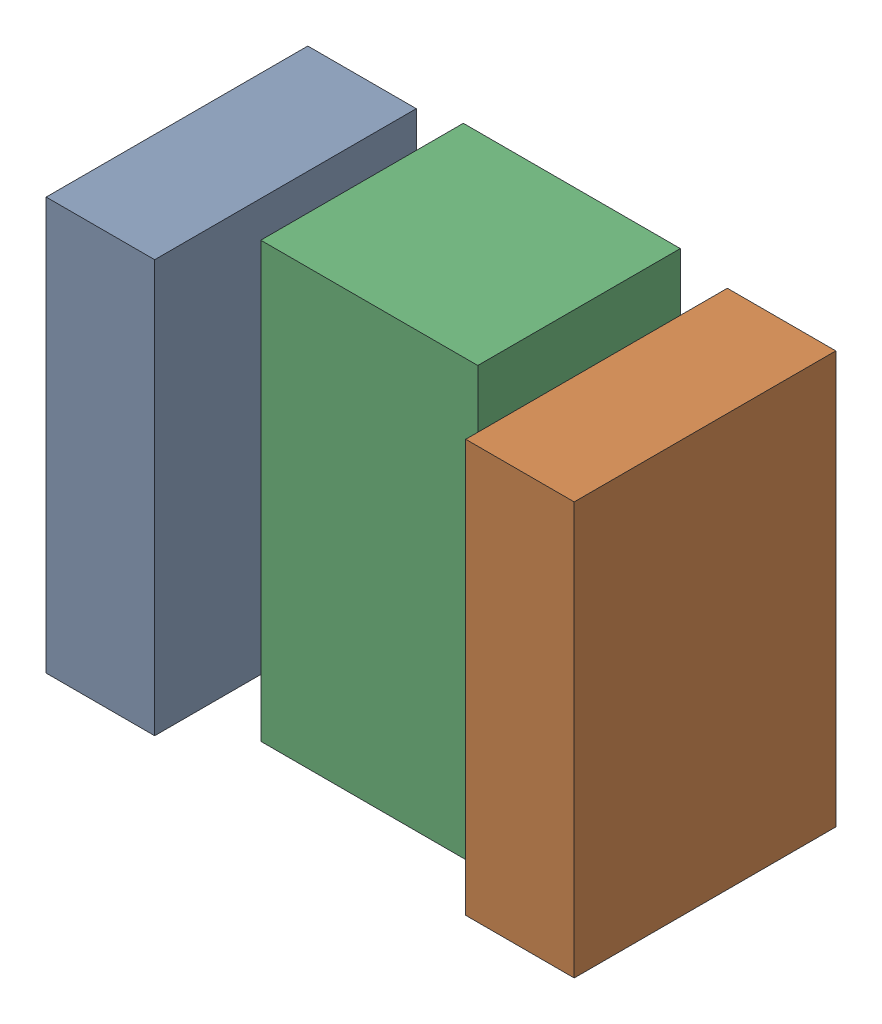
SolidWorks assembly C7_Motor_3Kanaloa_v2.0.0_Motor, configuration Default. Lengths in mm.
Overall size (3.65 3 1.81).
6 component instances, 2 part files, 0 mates.
Components (placement in the parent):
- 334788400-1: 334788400 [Default] at (59.721 84.582 0) size (0.75 2.85 1.81)
  - Extruded_5-1: Extruded_5 [Default] at origin size (0.75 2.85 1.81)
- 334788400-2: 334788400 [Default] at (62.621 84.582 0) size (0.75 2.85 1.81)
  - Extruded_5-1: Extruded_5 [Default] at origin size (0.75 2.85 1.81)
- 334788656-1: 334788656 [Default] at (61.171 84.582 0) size (1.5 3 1.4)
  - Extruded_1-1: Extruded_1 [Default] at origin size (1.5 3 1.4)
